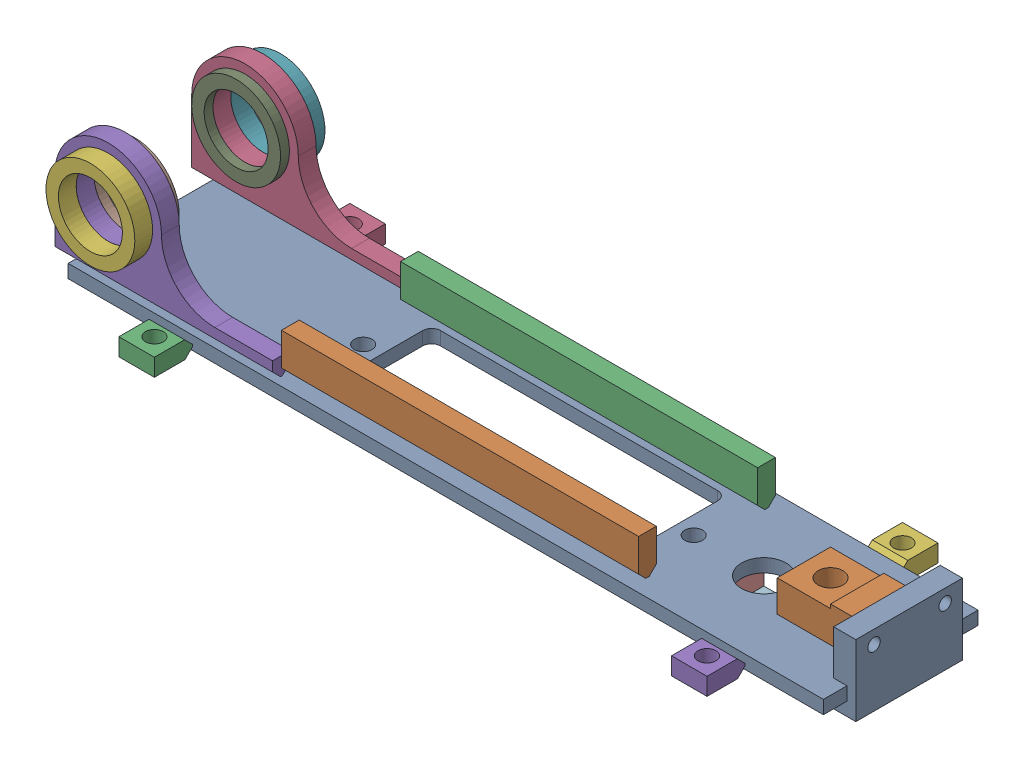
SolidWorks assembly g1_3_1_1_6_1, configuration 默认. Lengths in mm.
Overall size (875 200 260).
18 component instances, 14 part files, 0 mates.
Components (placement in the parent):
- g1_3_1_1_6-4_af0_1-1: g1_3_1_1_6-4_af0_1 [默认] at origin size (850 15 174)
- g1_3_1_1_6-8_1-1: g1_3_1_1_6-8_1 [默认] at (0 40 57) x (1 0 0) z (0 -1 0) size (402 20 44.8)
- g1_3_1_1_6-8_1-2: g1_3_1_1_6-8_1 [默认] at (0 40 -77) x (1 0 0) z (0 -1 0) size (402 20 44.8)
- g1_3_1_1_6-1_1-1: g1_3_1_1_6-1_1 [默认] at (-386 95 -87) x (1 0 0) z (0 -1 0) size (245 20 140)
- g1_3_1_1_6-1_1-2: g1_3_1_1_6-1_1 [默认] at (-386 95 67) x (1 0 0) z (0 -1 0) size (245 20 140)
- g1_3_1_1_6-3_1-1: g1_3_1_1_6-3_1 [默认] at (-386 95 87) x (-1 0 0) z (0 1 0) size (100 20 100)
- g1_3_1_1_6-3_1-2: g1_3_1_1_6-3_1 [默认] at (-386 95 -107) x (-1 0 0) z (0 1 0) size (100 20 100)
- g1_3_1_1_6-2_1-1: g1_3_1_1_6-2_1 [默认] at (-386 95 57) x (-1 0 0) z (0 1 0) size (100 10 100)
- g1_3_1_1_6-2_1-2: g1_3_1_1_6-2_1 [默认] at (-386 95 -57) x (1 0 0) z (0 1 0) size (100 10 100)
- g1_3_1_1_6-9_1-1: g1_3_1_1_6-9_1 [默认] at (220 -17 0) x (0 1 0) z (0 0 -1) size (35 15 60)
- g1_3_1_1_6-9_af0_1-1: g1_3_1_1_6-9_af0_1 [默认] at (310 -17 0) x (0 1 0) z (0 0 1) size (35 15 60)
- g1_3_1_1_6-10_1-1: g1_3_1_1_6-10_1 [默认] at (265 -45 0) size (60 20 60)
- g1_3_1_1_6-12_af0_1-1: g1_3_1_1_6-12_af0_1 [默认] at (434 25 0.5) x (0 0 1) z (0 -1 0) size (120 25 80)
- g1_3_1_1_6-11_af0_1-1: g1_3_1_1_6-11_af0_1 [默认] at (357 15 0) size (94 40 60)
- g1_3_1_1_6-5_af0_1-1: g1_3_1_1_6-5_af0_1 [默认] at (-311 -5 108.5) x (0 0 -1) z (1 0 0) size (43 19.6 40)
- g1_3_1_1_6-5_af1_1-1: g1_3_1_1_6-5_af1_1 [默认] at (-311 -5 -108.5) x (0 0 1) z (-1 0 0) size (43 19.6 40)
- g1_3_1_1_6-5_af2_1-1: g1_3_1_1_6-5_af2_1 [默认] at (311 -5 108.5) x (0 0 -1) z (1 0 0) size (43 19.6 40)
- g1_3_1_1_6-5_af3_1-1: g1_3_1_1_6-5_af3_1 [默认] at (311 -5 -108.5) x (0 0 1) z (-1 0 0) size (43 19.6 40)
